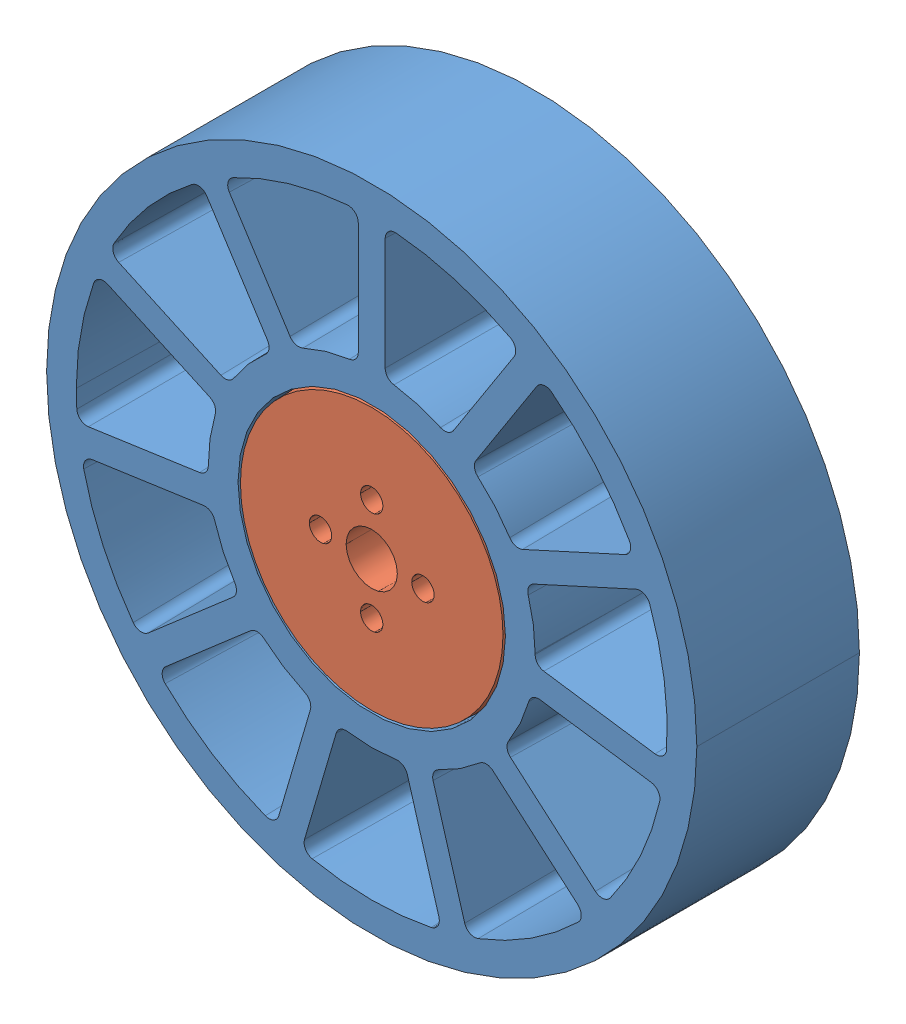
SolidWorks assembly am-3563 4IN 8mm Round Compliant Wheel REV2.STEP, configuration Default. Lengths in mm.
Overall size (101.6 101.6 25.74).
2 component instances, 2 part files, 0 mates.
Components (placement in the parent):
- 4IN Compliant Wheel FINAL Overmold.STEP-1: 4IN Compliant Wheel FINAL Overmold.STEP [Default] at (33.3747 9.5942 -11.4296) size (101.6 101.6 25.74)
- 2in Wheel Intergrated 8mm Hub.STEP-1: 2in Wheel Intergrated 8mm Hub.STEP [Default] at (33.3747 9.5942 -24.1296) size (41.91 41.91 25.4)
